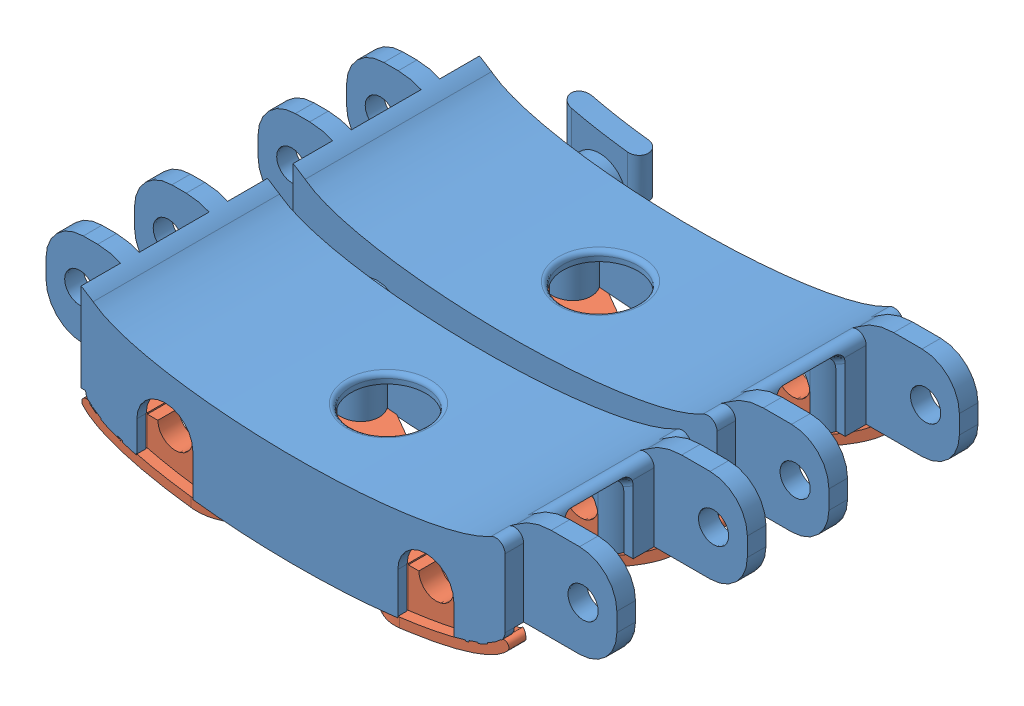
SolidWorks assembly ensamblaje 2eslabones paralelos con tapa nuevos, configuration Predeterminado. Lengths in mm.
Overall size (127 39.07 97.75).
5 component instances, 3 part files, 7 mates.
Components (placement in the parent):
- Soporte IR_10-1: Soporte IR_10 [Predeterminado] at (-10.4924 -4.2262 127) size (127 32.2 52.25)
- tapaSoporte IR_10-1: tapaSoporte IR_10 [Predeterminado] at (-10.4924 -3.9497 127) size (91.65 19.07 40)
- Pieza1^ensamblaje 2eslabones paralelos con tapa nuevos-1: Pieza1^ensamblaje 2eslabones paralelos con tapa nuevos [Predeterminado] at origin (virtual)
- Soporte IR_10-2: Soporte IR_10 [Predeterminado] at (-10.4924 -4.2262 81.5) size (127 32.2 52.25)
- tapaSoporte IR_10-3: tapaSoporte IR_10 [Predeterminado] at (-10.4924 -4.2262 81.5) size (91.65 19.07 40)
Mates (geometry in assembly coordinates):
- Concéntrica3: concentric: cylinder of Soporte IR_10-1 through (11.5076 15.7748 162.5) axis (0 -1 0) radius 2.5; cylinder of tapaSoporte IR_10-1 through (11.5076 -16.1499 162.5) axis (0 1 0) radius 2.25
- Paralelo4: parallel: plane of Soporte IR_10-1 through (-10.4924 15.7748 114.75) normal (0 0 -1); plane of tapaSoporte IR_10-1 through (-44.4924 -16.1499 129.25) normal (0 0 -1)
- Coincidente2: coincident: plane of Soporte IR_10-1 through (-10.4924 -4.2262 127) normal (0 -1 0); plane of tapaSoporte IR_10-1 through (-10.4924 -4.2262 167.001) normal (0 1 0)
- Concéntrica4: concentric: cylinder of Soporte IR_10-1 through (-32.4924 15.7748 117) axis (0 -1 0) radius 2.25; cylinder of Soporte IR_10-2 through (-32.4924 15.7748 117) axis (0 -1 0) radius 2.5
- Coincidente3: coincident: plane of Soporte IR_10-1 through (-10.4924 -4.2262 127) normal (0 -1 0); plane of Soporte IR_10-2 through (-10.4924 -4.2262 81.5) normal (0 -1 0)
- Concéntrica5: concentric: cylinder of Soporte IR_10-2 through (-44.4924 15.7748 117) axis (0 -1 0) radius 2.5; cylinder of tapaSoporte IR_10-3 through (-44.4924 -16.4264 117) axis (0 1 0) radius 2.25
- Coincidente4: coincident: plane of Soporte IR_10-2 through (-10.4924 -4.2262 81.5) normal (0 -1 0); plane of tapaSoporte IR_10-3 through (-44.4924 -4.2262 86) normal (0 1 0)
